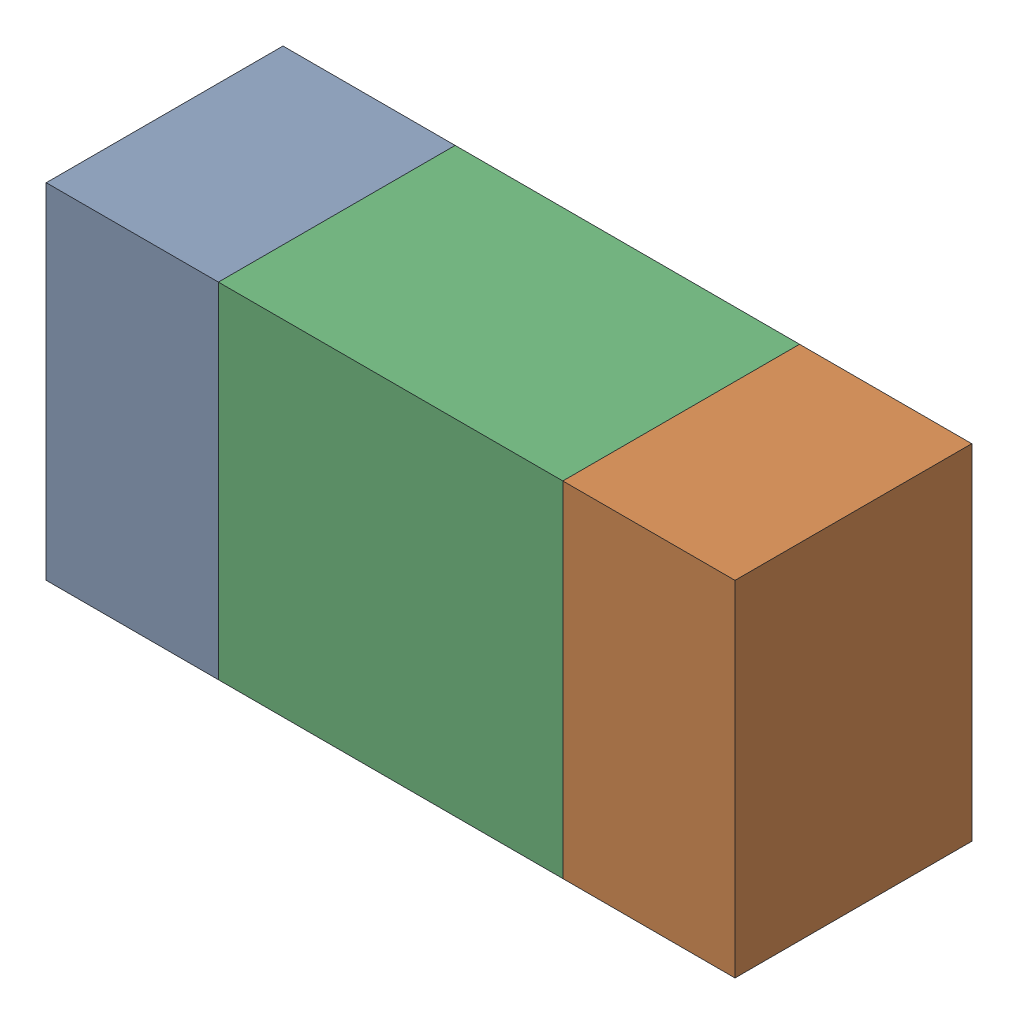
SolidWorks assembly R60, configuration ﾃﾞﾌｫﾙﾄ. Lengths in mm.
Overall size (1.6 0.8 0.55).
6 component instances, 2 part files, 0 mates.
Components (placement in the parent):
- 689261512-1: 689261512 [ﾃﾞﾌｫﾙﾄ] at (44.7001 29.0999 -1.7503) size (0.4 0.8 0.55)
  - Extruded_32-1: Extruded_32 [ﾃﾞﾌｫﾙﾄ] at origin size (0.4 0.8 0.55)
- 689261512-2: 689261512 [ﾃﾞﾌｫﾙﾄ] at (45.9001 29.0999 -1.7503) size (0.4 0.8 0.55)
  - Extruded_32-1: Extruded_32 [ﾃﾞﾌｫﾙﾄ] at origin size (0.4 0.8 0.55)
- 689261648-1: 689261648 [ﾃﾞﾌｫﾙﾄ] at (45.3 29.0999 -1.7503) size (0.8 0.8 0.55)
  - Extruded_33-1: Extruded_33 [ﾃﾞﾌｫﾙﾄ] at origin size (0.8 0.8 0.55)
